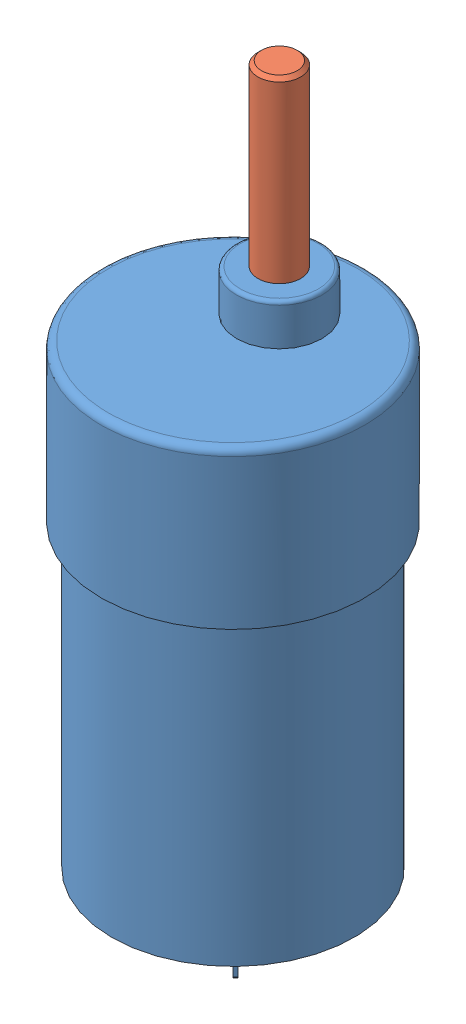
SolidWorks assembly Tetrix Motor, configuration Default. Lengths in mm.
Overall size (37 98.8 37).
2 component instances, 2 part files, 0 mates.
Components (placement in the parent):
- Tetrix Motor Body-1: Tetrix Motor Body [Default] at origin size (37 73.8 37)
- Tetrix Motor Shaft-1: Tetrix Motor Shaft [Default] at (0 27.8 -6.5) size (6 25 5.97)
